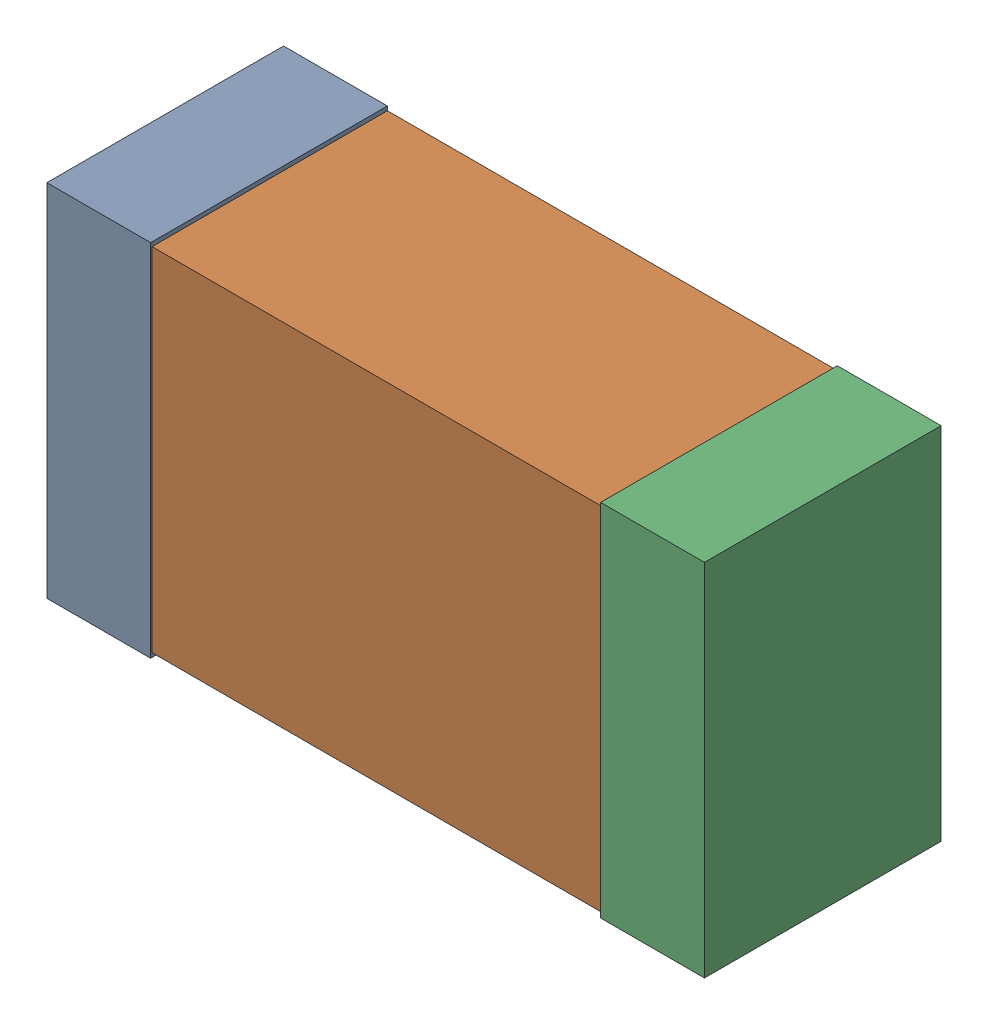
SolidWorks assembly R3Kanaloa_v2.0.0_GPIO_b, configuration Default. Lengths in mm.
Overall size (2.38 1.3 0.85).
6 component instances, 2 part files, 0 mates.
Components (placement in the parent):
- 352877648-1: 352877648 [Default] at (32.147 136.398 0) size (0.38 1.3 0.85)
  - Extruded_14-1: Extruded_14 [Default] at origin size (0.38 1.3 0.85)
- 352877392-1: 352877392 [Default] at (33.147 136.398 0) size (2.2 1.27 0.85)
  - Extruded_15-1: Extruded_15 [Default] at origin size (2.2 1.27 0.85)
- 352877648-2: 352877648 [Default] at (34.147 136.398 0) size (0.38 1.3 0.85)
  - Extruded_14-1: Extruded_14 [Default] at origin size (0.38 1.3 0.85)
